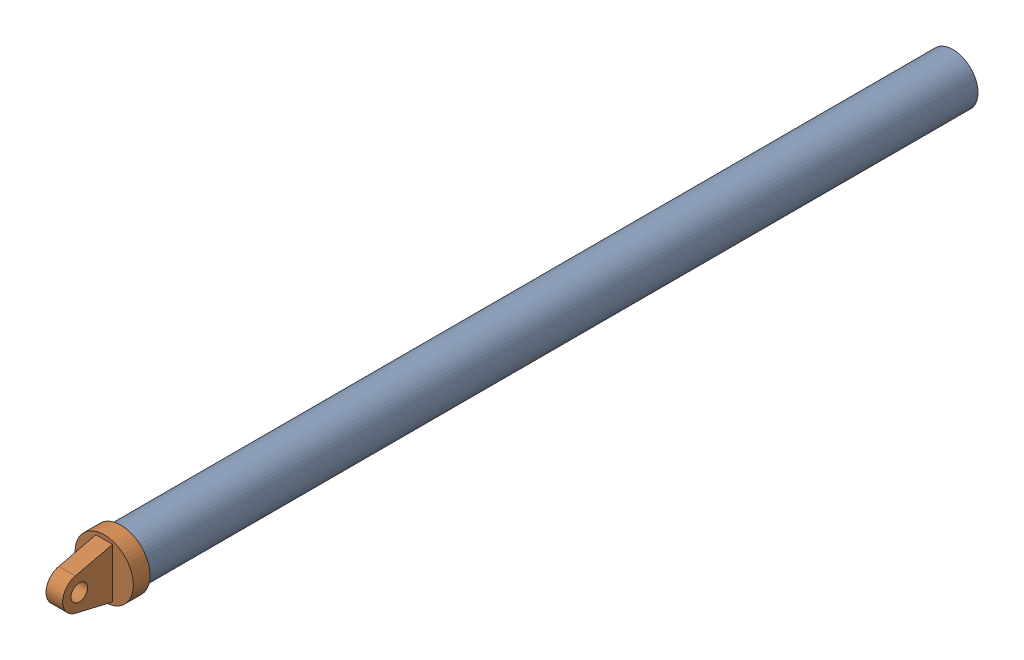
SolidWorks assembly 电推杆上部, configuration 默认. Lengths in mm.
Overall size (38.73 38.73 540).
2 component instances, 2 part files, 5 mates.
Components (placement in the parent):
- 电推杆2-1: 电推杆2 [默认] at (-314.2945 -272.618 -250) x (0.357025 -0.934095 0) z (0 0 1) size (30 30 500)
- 电推杆接头-1: 电推杆接头 [默认] at (5 4.4626 -25.1641) x (0 -1 0) z (-1 0 0) size (35 40 35)
Mates (geometry in assembly coordinates):
- 重合1: coincident anti-aligned: plane of 电推杆2-1 through (0 -5.4747 250) normal (0 0 1); plane of 电推杆接头-1 through (0 -5.4747 250) normal (0 0 -1)
- 同心1: concentric anti-aligned: cylinder of 电推杆2-1 through (0 -5.4747 250) axis (0 0 -1) radius 15; cylinder of 电推杆接头-1 through (0 -5.4747 250) axis (0 0 1) radius 17.5
- 对称2: symmetric aligned: plane of 电推杆接头-1 through (5 -1.0121 -25.1641) normal (1 0 0); plane of 电推杆接头-1 through (-5 -1.0121 -25.1641) normal (-1 0 0)
- 对称3: symmetric anti-aligned: plane of 电推杆2-1 through (0 -5.4747 -250) normal (0 0 -1); plane of 电推杆接头-1 through (0 -5.4747 250) normal (0 0 -1)
- 对称4: symmetric aligned: line of 电推杆接头-1 through (-5 9.5253 260) axis (1 0 0); line of 电推杆接头-1 through (-5 -20.4747 260) axis (1 0 0)
